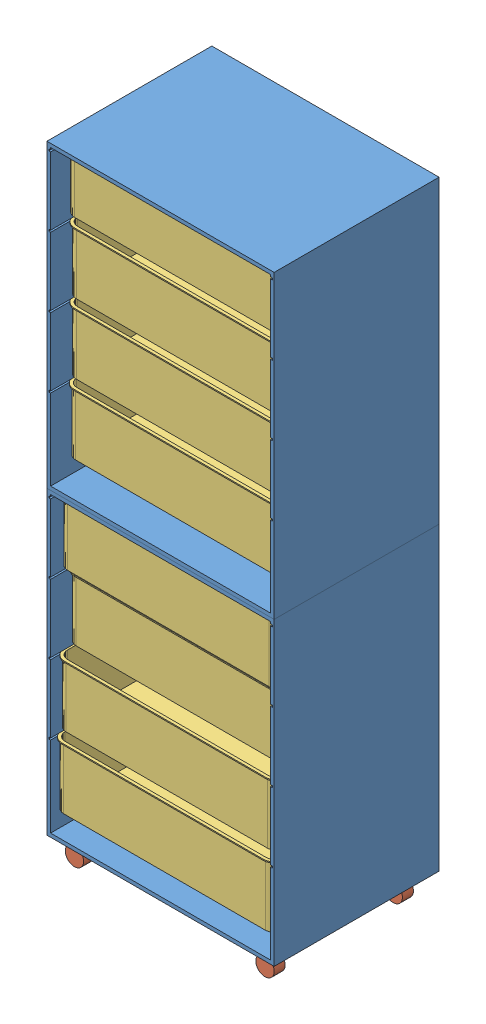
SolidWorks assembly large, configuration Default. Lengths in mm.
Overall size (620 1712 450.05).
14 component instances, 3 part files, 22 mates.
Components (placement in the parent):
- drawer-1: drawer [Default] at (-420.3474 -102.4158 291.3914) size (620 820 450)
- drawer-2: drawer [Default] at (-420.3474 717.5842 291.3914) size (620 820 450)
- rolls-1: rolls [Default] at (129.6526 -159.4158 326.3914) size (50 75 30)
- rolls-2: rolls [Default] at (-390.3474 -159.4158 676.3914) size (50 75 30)
- rolls-3: rolls [Default] at (-390.3474 -159.4158 326.3914) size (50 75 30)
- rolls-4: rolls [Default] at (129.6526 -159.4158 676.3914) size (50 75 30)
- box-1: box [Default] at (-420.3474 1150.2849 696.345) size (610 170 410)
- box-2: box [Default] at (-420.3474 960.2849 696.345) size (610 170 410)
- box-3: box [Default] at (-420.3474 770.2849 698.2867) size (610 170 410)
- box-4: box [Default] at (-425.2988 1340.2849 696.345) size (610 170 410)
- box-5: box [Default] at (-420.3474 520.2849 719.9882) size (610 170 410)
- box-6: box [Default] at (-420.3474 330.2849 696.844) size (610 170 410)
- box-7: box [Default] at (-420.3474 140.2849 723.8694) size (610 170 410)
- box-8: box [Default] at (-420.3474 -49.7151 730.5649) size (610 170 410)
Mates (geometry in assembly coordinates):
- Coincident1: coincident anti-aligned: plane of drawer-1 through (-420.3474 707.5842 741.3914) normal (0 1 0); plane of drawer-2 through (-420.3474 707.5842 741.3914) normal (0 -1 0)
- Coincident2: coincident aligned: line of drawer-1 through (189.6526 707.5842 741.3914) axis (0 0 -1); line of drawer-2 through (189.6526 707.5842 741.3914) axis (0 0 -1)
- Coincident3: coincident anti-aligned: line of drawer-1 through (189.6526 707.5842 741.3914) axis (-1 0 0); line of drawer-2 through (-430.3474 707.5842 741.3914) axis (1 0 0)
- Coincident4: coincident anti-aligned: circle of drawer-1; circle of rolls-4
- Coincident5: coincident anti-aligned: circle of drawer-1; circle of rolls-1
- Coincident6: coincident anti-aligned: circle of drawer-1; circle of rolls-2
- Coincident7: coincident anti-aligned: circle of drawer-1; circle of rolls-3
- Coincident8: coincident anti-aligned: plane of drawer-1 through (-425.3474 117.2849 1291.3914) normal (0 1 0); plane of box-8 through (-395.3474 117.2849 355.5649) normal (0 -1 0)
- Coincident9: coincident anti-aligned: line of drawer-1 through (-425.3474 117.2849 741.3914) axis (0 0 -1); line of box-8 through (-425.3474 117.2849 355.5649) axis (0 0 1)
- Coincident10: coincident anti-aligned: plane of drawer-1 through (-425.3474 307.2849 1291.3914) normal (0 1 0); plane of box-7 through (-395.3474 307.2849 348.8694) normal (0 -1 0)
- Coincident11: coincident anti-aligned: line of drawer-1 through (-425.3474 307.2849 741.3914) axis (0 0 -1); line of box-7 through (-425.3474 307.2849 348.8694) axis (0 0 1)
- Coincident12: coincident anti-aligned: plane of drawer-1 through (-425.3474 497.2849 1291.3914) normal (0 1 0); plane of box-6 through (-395.3474 497.2849 321.844) normal (0 -1 0)
- Coincident13: coincident anti-aligned: line of drawer-1 through (-425.3474 497.2849 741.3914) axis (0 0 -1); line of box-6 through (-425.3474 497.2849 321.844) axis (0 0 1)
- Coincident14: coincident anti-aligned: plane of drawer-1 through (-425.3474 687.2849 1291.3914) normal (0 1 0); plane of box-5 through (-395.3474 687.2849 344.9882) normal (0 -1 0)
- Coincident15: coincident anti-aligned: line of drawer-1 through (-425.3474 687.2849 741.3914) axis (0 0 -1); line of box-5 through (-425.3474 687.2849 344.9882) axis (0 0 1)
- Coincident16: coincident anti-aligned: plane of drawer-2 through (-425.3474 937.2849 1291.3914) normal (0 1 0); plane of box-3 through (-395.3474 937.2849 323.2867) normal (0 -1 0)
- Coincident17: coincident anti-aligned: line of drawer-2 through (-425.3474 937.2849 741.3914) axis (0 0 -1); line of box-3 through (-425.3474 937.2849 323.2867) axis (0 0 1)
- Coincident18: coincident anti-aligned: plane of drawer-2 through (-425.3474 1127.2849 1291.3914) normal (0 1 0); plane of box-2 through (-395.3474 1127.2849 321.345) normal (0 -1 0)
- Coincident19: coincident anti-aligned: line of drawer-2 through (-425.3474 1127.2849 741.3914) axis (0 0 -1); line of box-2 through (-425.3474 1127.2849 321.345) axis (0 0 1)
- Coincident20: coincident anti-aligned: plane of drawer-2 through (-425.3474 1317.2849 1291.3914) normal (0 1 0); plane of box-1 through (-395.3474 1317.2849 321.345) normal (0 -1 0)
- Coincident21: coincident anti-aligned: line of drawer-2 through (-425.3474 1317.2849 741.3914) axis (0 0 -1); line of box-1 through (-425.3474 1317.2849 321.345) axis (0 0 1)
- Coincident22: coincident anti-aligned: plane of drawer-2 through (-425.3474 1507.2849 1291.3914) normal (0 1 0); plane of box-4 through (-400.2988 1507.2849 321.345) normal (0 -1 0)
